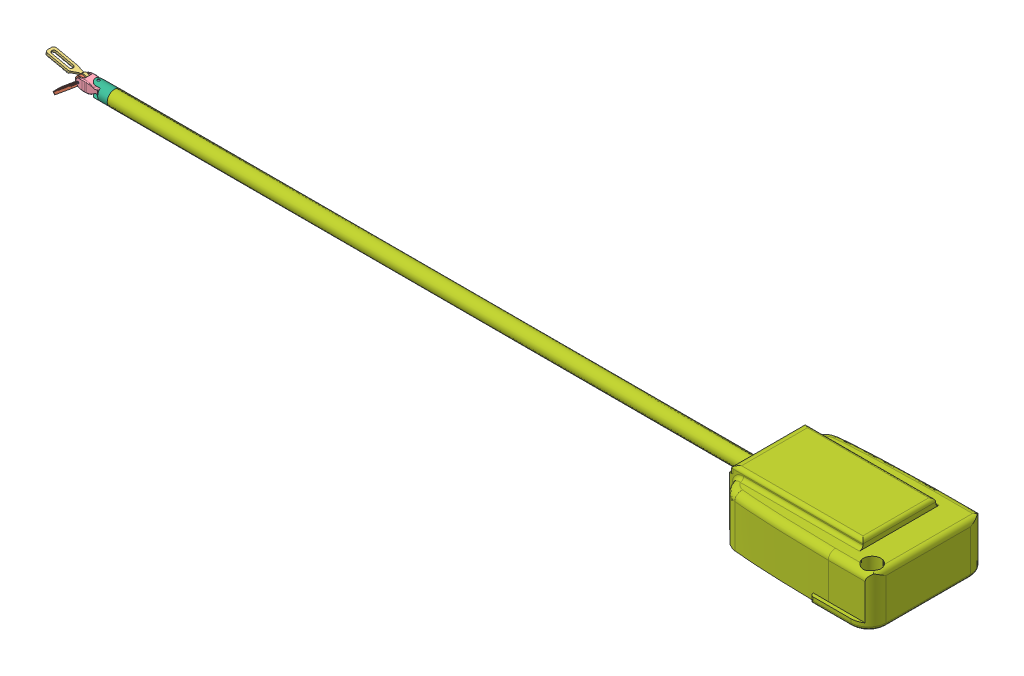
SolidWorks assembly Cadiere_Forceps, configuration Default. Lengths in mm.
Overall size (501.97 33 68.49).
7 component instances, 7 part files, 11 mates.
Components (placement in the parent):
- Tool_Wristis_Caudiere_Forceps_shaft_Link_2_3-1: Tool_Wristis_Caudiere_Forceps_shaft_Link_2_3 [Default] at (1.4545 -0.0718 -3.2188) size (1.3 1.3 5)
- Tool_Wristis_Caudiere_forceps_Link_3_Right-1: Tool_Wristis_Caudiere_forceps_Link_3_Right [Default] at (1.4545 -0.0718 -0.4688) x (-0.636961 0.770896 0) z (0 0 1) size (5 22.4 5.2)
- Tool_Wristis_Caudiere_forceps_Link_3_Left-1: Tool_Wristis_Caudiere_forceps_Link_3_Left [Default] at (1.4545 -0.0718 -1.0688) x (-0.214181 -0.976794 0) z (0 0 -1) size (5 22.4 5.2)
- Tool_Wristis_Caudier_Forceps_Link_2-1: Tool_Wristis_Caudier_Forceps_Link_2 [Default] at (5.2545 -0.0718 -3.9188) size (13.22 7.35 6.88)
- Tool_Wrists_Shaft_Link_1_2-1: Tool_Wrists_Shaft_Link_1_2 [Default] at (10.3545 -4.0918 -0.7188) x (1 0 0) z (0 1 0) size (1.3 1.3 8.02)
- Tool_Wrists_Link_1-1: Tool_Wrists_Link_1 [Default] at (19.4545 -0.0718 -0.7188) x (0 1 0) z (-1 0 0) size (8.32 8.32 11)
- Tool_main-1: Tool_main [Default] at (386.2545 -0.0718 -0.7188) x (0 0 1) z (-1 0 0) size (68.49 33 464)
Mates (geometry in assembly coordinates):
- Coincident1: coincident anti-aligned: cylinder of Tool_Wristis_Caudiere_Forceps_shaft_Link_2_3-1; circle of Tool_Wristis_Caudier_Forceps_Link_2-1
- Distance1: distance = 4.5 mm aligned: plane of Tool_Wristis_Caudiere_Forceps_shaft_Link_2_3-1 through (1.4545 -0.0718 1.7812) normal (0 0 1); plane of Tool_Wristis_Caudier_Forceps_Link_2-1 through (-0.7455 -3.7471 -2.7188) normal (0 0 1)
- Coincident3: coincident anti-aligned: plane of Tool_Wristis_Caudiere_forceps_Link_3_Right-1 through (1.4545 -0.0718 1.1812) normal (0 0 1); plane of Tool_Wristis_Caudier_Forceps_Link_2-1 through (-0.7455 -3.7471 1.1812) normal (0 0 -1)
- Concentric1: concentric anti-aligned: cylinder of Tool_Wristis_Caudiere_Forceps_shaft_Link_2_3-1; cylinder of Tool_Wristis_Caudiere_forceps_Link_3_Right-1
- Coincident4: coincident anti-aligned: plane of Tool_Wristis_Caudiere_forceps_Link_3_Left-1 through (1.4545 -0.0718 -2.7188) normal (0 0 -1); plane of Tool_Wristis_Caudier_Forceps_Link_2-1 through (-0.7455 -3.7471 -2.7188) normal (0 0 1)
- Concentric2: concentric aligned: cylinder of Tool_Wristis_Caudiere_Forceps_shaft_Link_2_3-1; cylinder of Tool_Wristis_Caudiere_forceps_Link_3_Left-1
- Concentric3: concentric anti-aligned: cylinder of Tool_Wrists_Shaft_Link_1_2-1; cylinder of Tool_Wrists_Link_1-1
- Distance2: distance = 7.2 mm aligned: plane of Tool_Wrists_Shaft_Link_1_2-1 through (10.3545 3.9282 -0.7188) normal (0 1 0); plane of Tool_Wrists_Link_1-1 through (7.5971 -3.2718 3.4412) normal (0 1 0)
- Concentric4: concentric anti-aligned: cylinder of Tool_Wristis_Caudier_Forceps_Link_2-1; cylinder of Tool_Wrists_Shaft_Link_1_2-1
- Distance4: distance = 2.2 mm anti-aligned: plane of Tool_Wristis_Caudier_Forceps_Link_2-1 through (12.7545 -1.0718 2.3812) normal (0 -1 0); plane of Tool_Wrists_Link_1-1 through (7.5971 -3.2718 3.4412) normal (0 1 0)
- LimitAngle1: limit planar angle = 0.906404 rad anti-aligned: plane of Tool_Wristis_Caudiere_forceps_Link_3_Left-1 through (-16.7961 4.2372 1.8312) normal (-0.214181 -0.976794 0); plane of Tool_Wristis_Caudiere_forceps_Link_3_Right-1 through (-13.8863 -12.7473 -3.3688) normal (-0.636961 0.770896 0)
